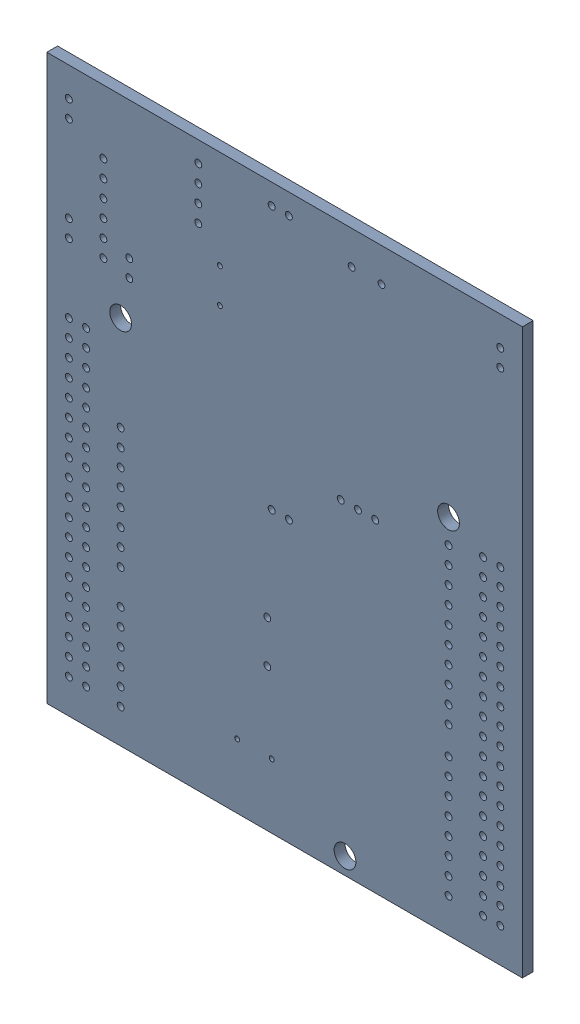
SolidWorks assembly MB1136, configuration Default. Lengths in mm.
Overall size (70 83 1.59).
2 component instances, 1 part files, 0 mates.
Components (placement in the parent):
- Board-1: Board [Default] at origin size (70 83 1.59)
  - Open CASCADE STEP translator 7.5 2.1.1-1: Open CASCADE STEP translator 7.5 2.1.1 [Default] at (0 0 -1.5914) size (70 83 1.59)
